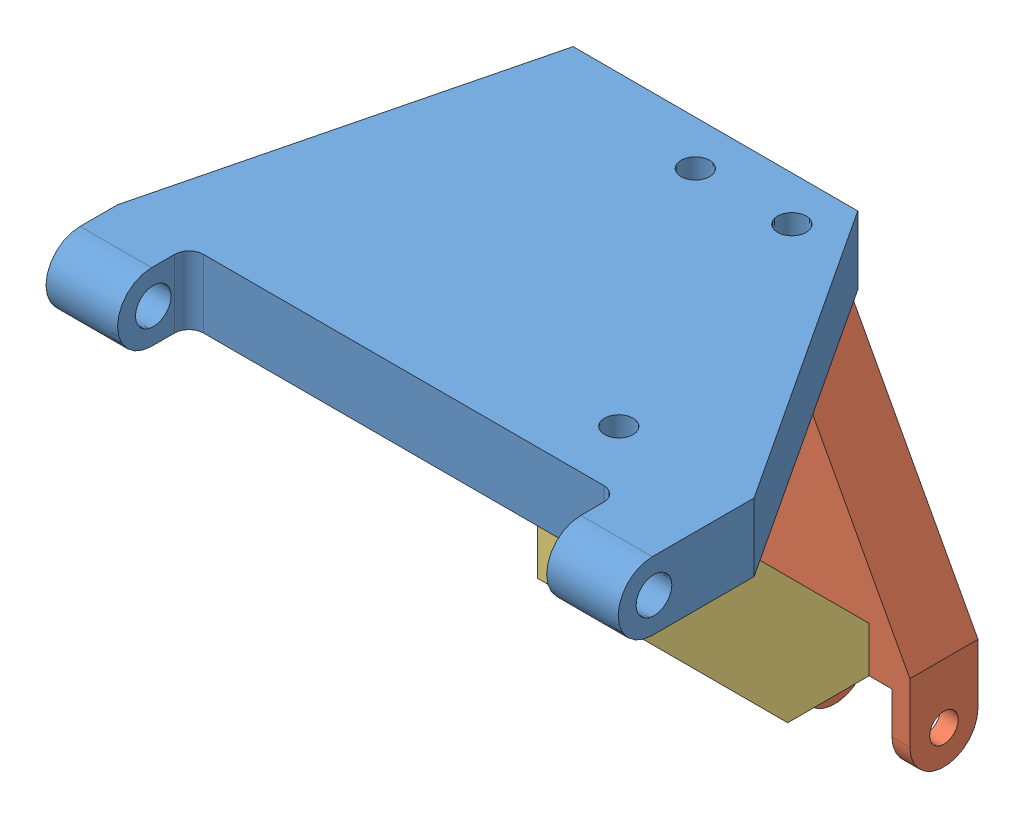
SolidWorks assembly Sm, configuration Default. Lengths in mm.
Overall size (160 110.2 122).
3 component instances, 3 part files, 8 mates.
Components (placement in the parent):
- BottomWishbone-1: BottomWishbone [Default] at origin size (160 19.05 122)
- BottomShock mount-1: BottomShock mount [Default] at (141.5 3.4314 16.4036) x (0 0 -1) z (-1 0 0) size (19.05 91.15 87)
- ShockBrace-1: ShockBrace [Default] x (-1 0 0) z (0 -1 0) size (12.7 80.25 70.19)
Mates (geometry in assembly coordinates):
- Coincident6: coincident anti-aligned: plane of BottomWishbone-1 through (0 0 0) normal (0 -1 0); plane of BottomShock mount-1 through (141.5 0 16.4036) normal (0 1 0)
- Parallel2: parallel anti-aligned: line of BottomWishbone-1 through (0 79.6 105) axis (0 0 -1); line of BottomShock mount-1 through (54.5 0 2.8892) axis (1 0 0)
- Concentric2: concentric aligned: circle of BottomWishbone-1; circle of BottomShock mount-1
- Parallel3: parallel aligned: line of BottomWishbone-1 through (0 79.6 105) axis (0 0 -1); line of BottomShock mount-1 through (141.5 0 2.8892) axis (-1 0 0)
- InPlace1: in place: plane of BottomWishbone-1 through (0 0 0) normal (0 -1 0); plane of ShockBrace-1 through (0 0 0) normal (0 -1 0); moOrthogonalPlaneRef_w of BottomWishbone-1 through (0 0 0) normal (0 -1 0); plane of ShockBrace-1 through (0 0 0) normal (0 0 -1); plane of BottomWishbone-1 through (0 0 0) normal (0 -1 0); plane of ShockBrace-1 through (0 0 0) normal (-1 0 0); plane of BottomWishbone-1 through (0 0 0) normal (0 -1 0); unknown of ShockBrace-1
- Coincident10: coincident aligned: plane of ?; plane of ?
- Coincident11: coincident aligned: moOrthogonalPlaneRef_w of BottomWishbone-1 through (0 0 0) normal (0 0 -1); plane of Part1^Sm-1 through (0 0 0) normal (0 0 -1)
- Coincident12: coincident anti-aligned: moOrthogonalPlaneRef_w of BottomWishbone-1 through (0 0 0) normal (1 0 0); plane of Part1^Sm-1 through (0 0 0) normal (-1 0 0)
